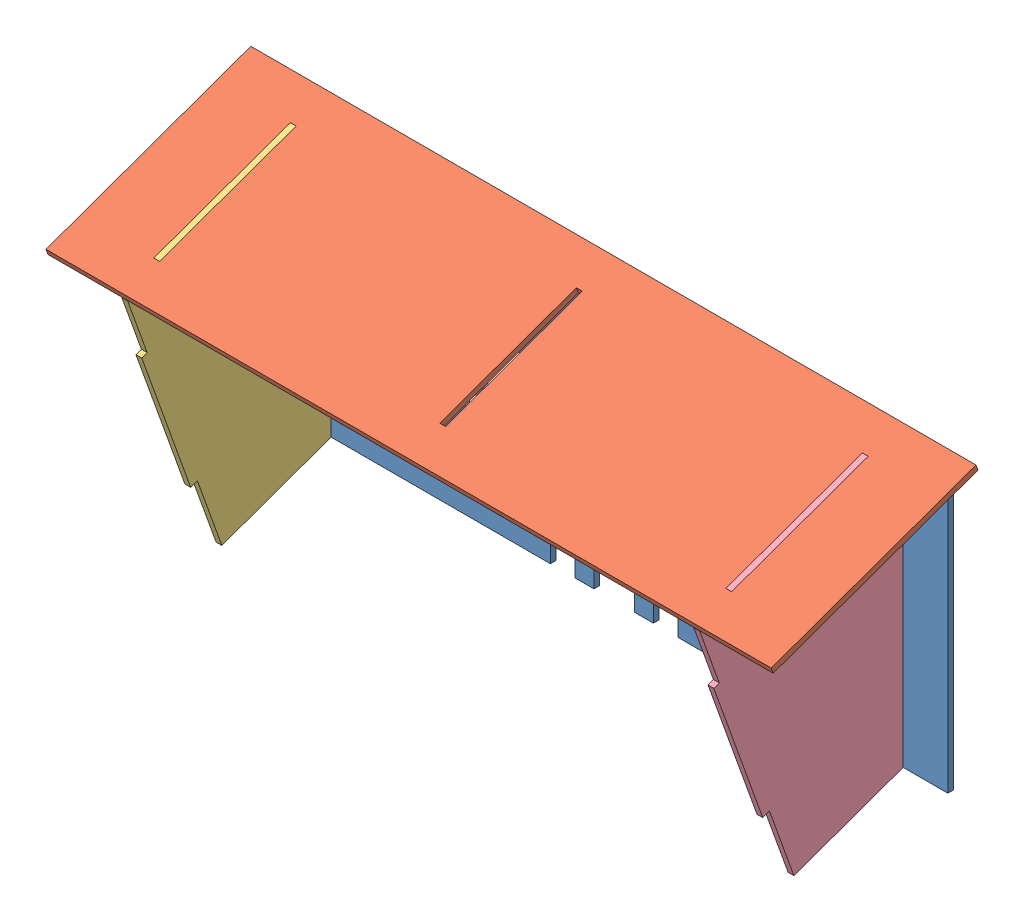
SolidWorks assembly New电机装配体, configuration 默认. Lengths in mm.
Overall size (250 117.45 104.89).
4 component instances, 4 part files, 9 mates.
Components (placement in the parent):
- 电机支架-顶部-1: 电机支架-顶部 [默认] at (-61.2572 53.6101 229) size (230 100 2)
- 电机支架-前-1: 电机支架-前 [默认] at (-46.6202 49.3143 304.3877) x (1 0 0) z (0 0.941294 0.337587) size (250 75 2)
- 电机支架-右侧面-1: 电机支架-右侧面 [默认] at (-92.902 34.7745 255.3989) x (0 0.941294 0.337587) z (-1 0 0) size (97.16 76.58 2)
- 电机支架-左侧面-1: 电机支架-左侧面 [默认] at (104.298 34.7745 255.3989) x (0 0.941294 0.337587) z (-1 0 0) size (97.16 76.58 2)
Mates (geometry in assembly coordinates):
- 重合8: coincident anti-aligned: plane of 电机支架-顶部-1 through (-94.902 49.5341 231) normal (1 0 0); plane of 电机支架-右侧面-1 through (-94.902 34.7745 255.3989) normal (-1 0 0)
- 重合9: coincident anti-aligned: plane of 电机支架-顶部-1 through (-94.902 49.5341 231) normal (0 -1 0); plane of 电机支架-右侧面-1 through (-94.902 49.5341 231) normal (0 1 0)
- 重合10: coincident anti-aligned: plane of 电机支架-顶部-1 through (-61.2572 53.6101 231) normal (0 0 1); plane of 电机支架-右侧面-1 through (-94.902 -0.4659 231) normal (0 0 -1)
- 重合22: coincident anti-aligned: plane of 电机支架-顶部-1 through (104.298 49.5341 231) normal (-1 0 0); plane of 电机支架-左侧面-1 through (104.298 34.7745 255.3989) normal (1 0 0)
- 重合23: coincident anti-aligned: plane of 电机支架-顶部-1 through (104.298 49.5341 231) normal (0 -1 0); plane of 电机支架-左侧面-1 through (102.298 49.5341 231) normal (0 1 0)
- 重合24: coincident anti-aligned: plane of 电机支架-顶部-1 through (-61.2572 53.6101 231) normal (0 0 1); plane of 电机支架-左侧面-1 through (102.298 75.6341 231) normal (0 0 -1)
- 重合25: coincident: line of 电机支架-前-1 through (104.298 56.5593 290.1107) axis (0 0.337587 -0.941294); plane of 电机支架-左侧面-1 through (104.298 34.7745 255.3989) normal (1 0 0)
- 重合26: coincident anti-aligned: plane of 电机支架-前-1 through (104.298 73.4387 243.046) normal (0 -0.337587 0.941294); plane of 电机支架-左侧面-1 through (102.298 71.5561 242.3708) normal (0 0.337587 -0.941294)
- 重合27: coincident anti-aligned: plane of 电机支架-前-1 through (-46.6202 49.3143 304.3877) normal (0 -0.941294 -0.337587); plane of 电机支架-左侧面-1 through (102.298 71.5561 242.3708) normal (0 0.941294 0.337587)
